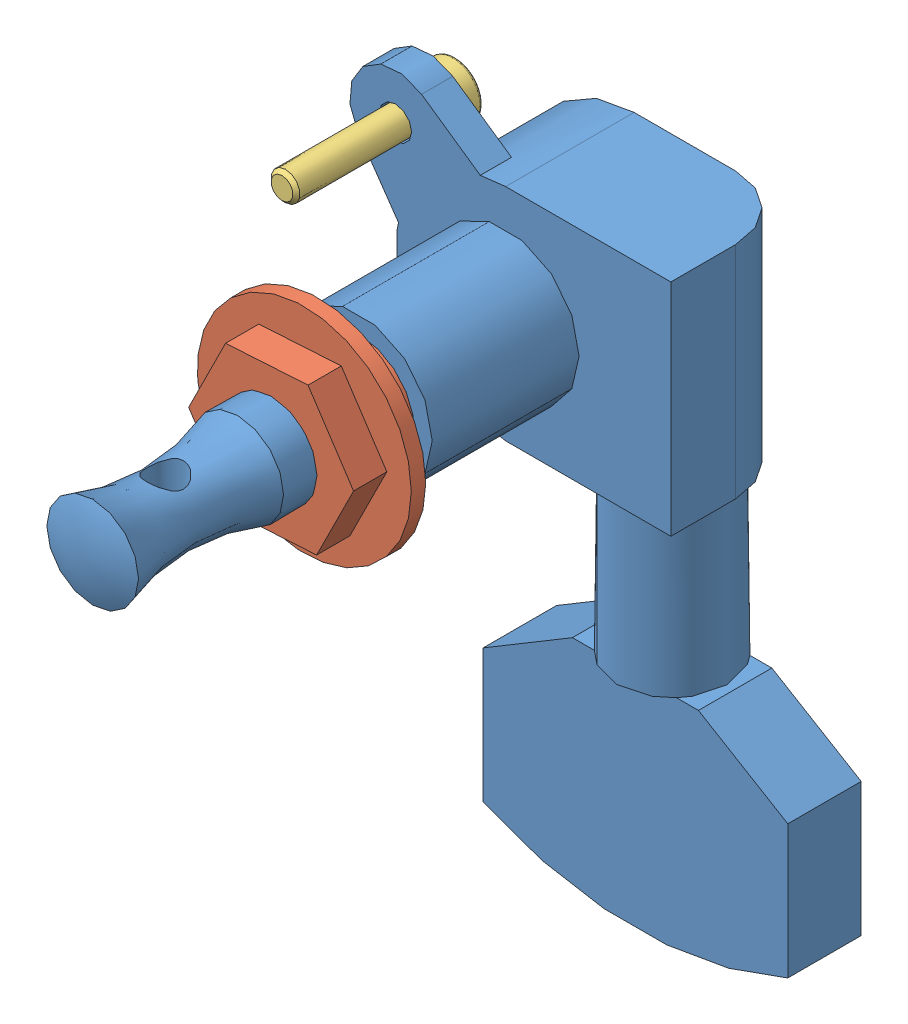
SolidWorks assembly tuning peg, configuration Default. Lengths in mm.
Overall size (28.38 45.1 38.1).
3 component instances, 3 part files, 9 mates.
Components (placement in the parent):
- TUNING PEG-1: TUNING PEG [Default] at origin size (28.38 45.1 38.1)
- TUNING PEG RETAINER-1: TUNING PEG RETAINER [Default] at (0 0 10.6686) x (-0.998189 -0.060152 0) z (0 0 1) size (14.8 14.8 14.45)
- M2X10-1: M2X10 [Default] at (-7.6332 7.6332 6.731) x (0 0 1) z (1 0 0) size (12 3.8 3.8)
Mates (geometry in assembly coordinates):
- Concentric116: concentric anti-aligned: cylinder of TUNING PEG-1 through (0 0 8.89) axis (0 0 1) radius 5.08; cylinder of ? through (-0.0002 0.0002 38.89) axis (0 0 -1) radius 5.08
- Coincident205: coincident anti-aligned: plane of TUNING PEG-1 through (3.8845 0 8.89) normal (0 0 1); plane of ? through (-0.0002 0.0002 8.89) normal (0 0 -1)
- Concentric118: concentric anti-aligned: cylinder of TUNING PEG-1 through (0 0 23.241) axis (0 0 -1) radius 3.175; cylinder of TUNING PEG RETAINER-1 through (0 0 10.6686) axis (0 0 1) radius 3.125
- Concentric119: concentric anti-aligned: cylinder of TUNING PEG-1 through (-7.6332 7.6332 8.89) axis (0 0 -1) radius 1.125; cylinder of M2X10-1 through (-7.6332 7.6332 12.2537) axis (0 0 1) radius 1
- Coincident207: coincident anti-aligned: plane of TUNING PEG-1 through (-6.8243 6.8243 6.731) normal (0 0 -1); plane of M2X10-1 through (-7.6332 6.1832 6.731) normal (0 0 1)
- Coincident208: coordinate: point of TUNING PEG-1; point of assembly
- Parallel1: parallel aligned: plane of TUNING PEG RETAINER-1; plane of ? through (17.4998 -16.2498 23.89) normal (0 -1 0)
- Concentric120: concentric aligned: cylinder of TUNING PEG-1 through (-7.6332 7.6332 8.89) axis (0 0 -1) radius 1.125; cylinder of ? through (-7.6332 7.6332 23.59) axis (0 0 -1) radius 1
- Coincident209: coincident anti-aligned: plane of TUNING PEG RETAINER-1 through (0 0 23.89) normal (0 0 -1); plane of ? through (-0.0002 0.0002 23.89) normal (0 0 1)
